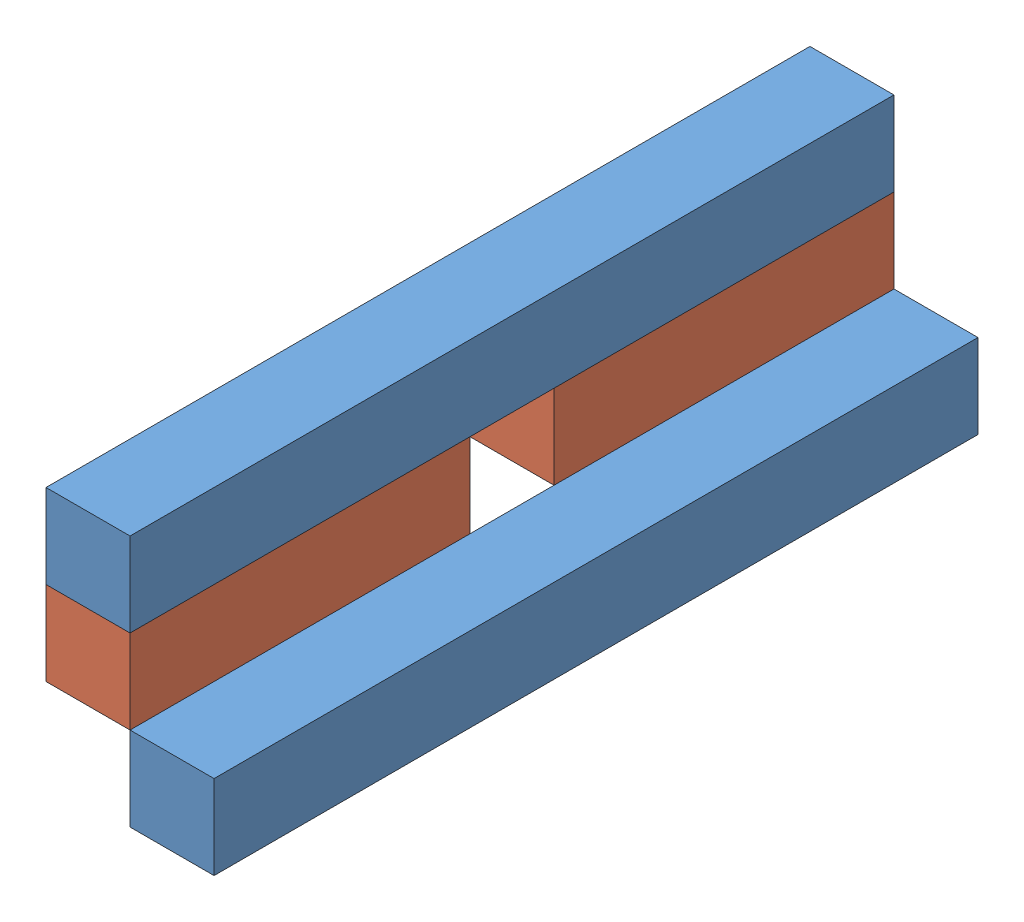
SolidWorks assembly fixation_message, configuration Default. Lengths in mm.
Overall size (44 66 200).
4 component instances, 2 part files, 9 mates.
Components (placement in the parent):
- linteau_22x22_L200_bleu-1: linteau_22x22_L200_bleu [Default] at (-38.927 5.771 103.3427) size (22 22 200)
- linteau_22x22_L89_bleu-1: linteau_22x22_L89_bleu [Default] at (-38.927 -16.229 103.3427) size (22 22 89)
- linteau_22x22_L89_bleu-2: linteau_22x22_L89_bleu [Default] at (-38.927 -16.229 -7.6573) size (22 22 89)
- linteau_22x22_L200_bleu-2: linteau_22x22_L200_bleu [Default] at (-16.927 -38.229 103.3427) size (22 22 200)
Mates (geometry in assembly coordinates):
- Coïncidente1: coincident: plane of linteau_22x22_L200_bleu-1 through (-38.927 27.771 103.3427) normal (0 0 1); plane of linteau_22x22_L89_bleu-1 through (-38.927 5.771 103.3427) normal (0 0 1)
- Coïncidente2: coincident: plane of linteau_22x22_L200_bleu-1 through (-16.927 5.771 -96.6573) normal (1 0 0); plane of linteau_22x22_L89_bleu-1 through (-16.927 -16.229 14.3427) normal (1 0 0)
- Coïncidente3: coincident anti-aligned: plane of linteau_22x22_L200_bleu-1 through (-38.927 5.771 -96.6573) normal (0 -1 0); plane of linteau_22x22_L89_bleu-1 through (-38.927 5.771 14.3427) normal (0 1 0)
- Coïncidente4: coincident: plane of linteau_22x22_L200_bleu-1 through (-38.927 27.771 -96.6573) normal (0 0 -1); plane of linteau_22x22_L89_bleu-2 through (-38.927 5.771 -96.6573) normal (0 0 -1)
- Coïncidente5: coincident: plane of linteau_22x22_L200_bleu-1 through (-38.927 5.771 -96.6573) normal (0 -1 0); plane of linteau_22x22_L89_bleu-2 through (-38.927 5.771 -96.6573) normal (0 1 0)
- Coïncidente6: coincident aligned: plane of linteau_22x22_L200_bleu-1 through (-16.927 5.771 -96.6573) normal (1 0 0); plane of linteau_22x22_L89_bleu-2 through (-16.927 -16.229 -96.6573) normal (1 0 0)
- Coïncidente7: coincident: line of linteau_22x22_L89_bleu-1; line of linteau_22x22_L200_bleu-2
- Coïncidente8: coincident: plane of linteau_22x22_L89_bleu-1 through (-38.927 5.771 103.3427) normal (0 0 1); plane of linteau_22x22_L200_bleu-2 through (-16.927 -16.229 103.3427) normal (0 0 1)
- Coïncidente9: coincident anti-aligned: plane of linteau_22x22_L89_bleu-1 through (-16.927 -16.229 14.3427) normal (1 0 0); plane of linteau_22x22_L200_bleu-2 through (-16.927 -38.229 -96.6573) normal (-1 0 0)
